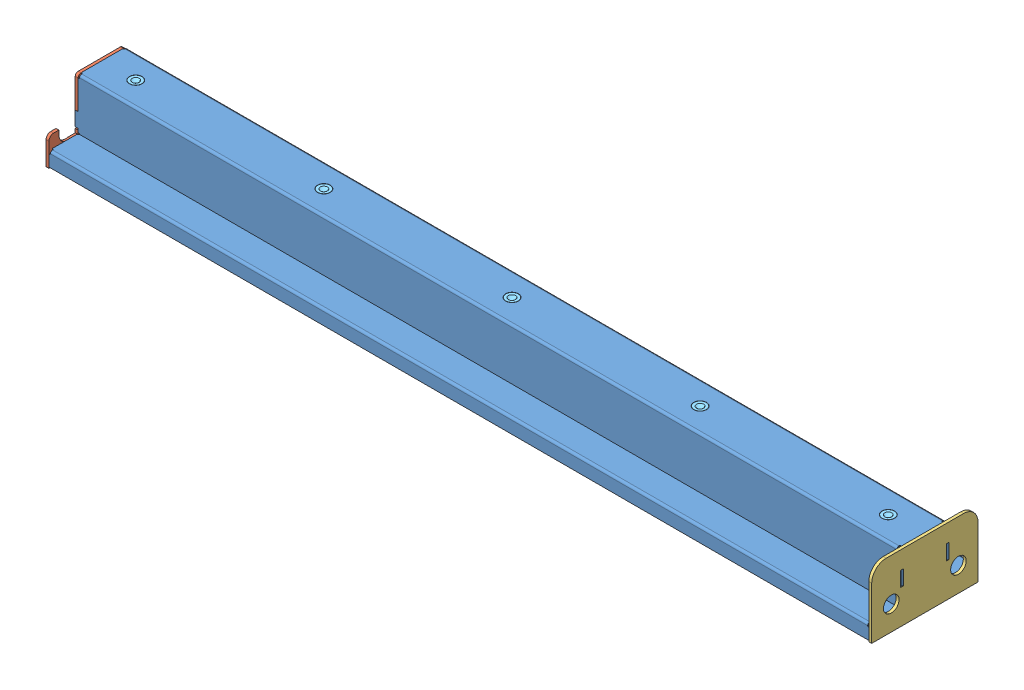
SolidWorks assembly 凸輪軌道座-中, configuration 預設. Lengths in mm.
Overall size (856 69.59 110.4).
10 component instances, 5 part files, 12 mates.
Components (placement in the parent):
- LB-A54-12-2-1: LB-A54-12-2 [預設] at (-530.5548 -8.8562 -24.71) size (856 68.08 109.86)
- LB-A54-12-8-1: LB-A54-12-8 [預設] at (-530.5548 17.0438 55.01) x (0 0 -1) z (1 0 0) size (110.2 69 3)
- LB-A54-12-7-2: LB-A54-12-7 [預設] at (325.4452 17.2038 -54.99) x (0 0 1) z (-1 0 0) size (110.2 69 3)
- LB-A54-12-9-1: LB-A54-12-9 [預設] at (-245.0548 17.4038 52.63) x (0 0 -1) z (1 0 0) size (104.6 66.5 3)
- LB-A54-12-9-2: LB-A54-12-9 [預設] at (39.9452 17.4038 52.63) x (0 0 -1) z (1 0 0) size (104.6 66.5 3)
- 2分半點焊螺帽-1: 2分半點焊螺帽 [預設] at (-492.5548 78.7038 0) x (-0.002666 0 -0.999996) z (0.999996 0 -0.002666) size (18.22 7.93 18.22)
- 2分半點焊螺帽-2: 2分半點焊螺帽 [預設] at (-297.5548 78.7038 0) x (-0.002666 0 -0.999996) z (0.999996 0 -0.002666) size (18.22 7.93 18.22)
- 2分半點焊螺帽-3: 2分半點焊螺帽 [預設] at (-102.5548 78.7038 0) x (-0.002666 0 -0.999996) z (0.999996 0 -0.002666) size (18.22 7.93 18.22)
- 2分半點焊螺帽-4: 2分半點焊螺帽 [預設] at (92.4452 78.7038 0) x (-0.002666 0 -0.999996) z (0.999996 0 -0.002666) size (18.22 7.93 18.22)
- 2分半點焊螺帽-5: 2分半點焊螺帽 [預設] at (287.4452 78.7038 0) x (-0.002666 0 -0.999996) z (0.999996 0 -0.002666) size (18.22 7.93 18.22)
Mates (geometry in assembly coordinates):
- 重合/共線/共點6: coincident anti-aligned: plane of LB-A54-12-2-1 through (-527.5548 83.9038 21.25) normal (-1 0 0); plane of LB-A54-12-8-1 through (-527.5548 41.2438 -50.19) normal (1 0 0)
- 重合/共線/共點7: coincident aligned: plane of LB-A54-12-2-1 through (-527.5548 129.7438 24.71) normal (0 0 1); plane of LB-A54-12-8-1 through (-527.5548 83.0438 24.71) normal (0 0 1)
- 重合/共線/共點8: coincident anti-aligned: plane of LB-A54-12-2-1 through (-530.5548 52.7438 22.41) normal (0 1 0); plane of LB-A54-12-8-1 through (-527.5548 52.7438 24.71) normal (0 -1 0)
- 重合/共線/共點12: coincident anti-aligned: plane of LB-A54-12-2-1 through (322.4452 83.9038 -21.25) normal (1 0 0); plane of LB-A54-12-7-2 through (322.4452 71.2038 40.21) normal (-1 0 0)
- 重合/共線/共點13: coincident anti-aligned: plane of LB-A54-12-2-1 through (-527.5548 129.7438 22.41) normal (0 0 -1); plane of LB-A54-12-7-2 through (322.4452 52.4038 22.41) normal (0 0 1)
- 重合/共線/共點14: coincident aligned: plane of LB-A54-12-2-1 through (-527.5548 86.2038 -22.75) normal (0 1 0); plane of LB-A54-12-7-2 through (322.4452 86.2038 40.21) normal (0 1 0)
- 重合/共線/共點15: coincident anti-aligned: plane of LB-A54-12-2-1 through (-527.5548 83.9038 -22.75) normal (0 -1 0); plane of LB-A54-12-9-1 through (-242.0548 83.9038 -18.67) normal (0 1 0)
- 重合/共線/共點17: coincident anti-aligned: plane of LB-A54-12-2-1 through (-527.5548 156.7238 52.63) normal (0 0 -1); plane of LB-A54-12-9-1 through (-242.0548 27.1038 52.63) normal (0 0 1)
- 平行相距1: distance = 282.5 mm anti-aligned: plane of LB-A54-12-9-1 through (-245.0548 27.1038 -48.97) normal (-1 0 0); plane of LB-A54-12-8-1 through (-527.5548 41.2438 -50.19) normal (1 0 0)
- 同軸心1: concentric aligned: cylinder of LB-A54-12-2-1 through (-492.5548 83.9038 0) axis (0 1 0) radius 6.6; cylinder of 2分半點焊螺帽-1 through (-492.5548 88.6719 0) axis (0 1 0) radius 6.5
- 重合/共線/共點18: coincident aligned: plane of LB-A54-12-2-1 through (-527.5548 86.2038 -22.75) normal (0 1 0); plane of 2分半點焊螺帽-1 through (-501.7471 86.2038 0.0245) normal (0 1 0)
- 局部直線複製2: unknown: line of LB-A54-12-2-1 through (-526.0938 83.9038 22.41) axis (1 0 0)
